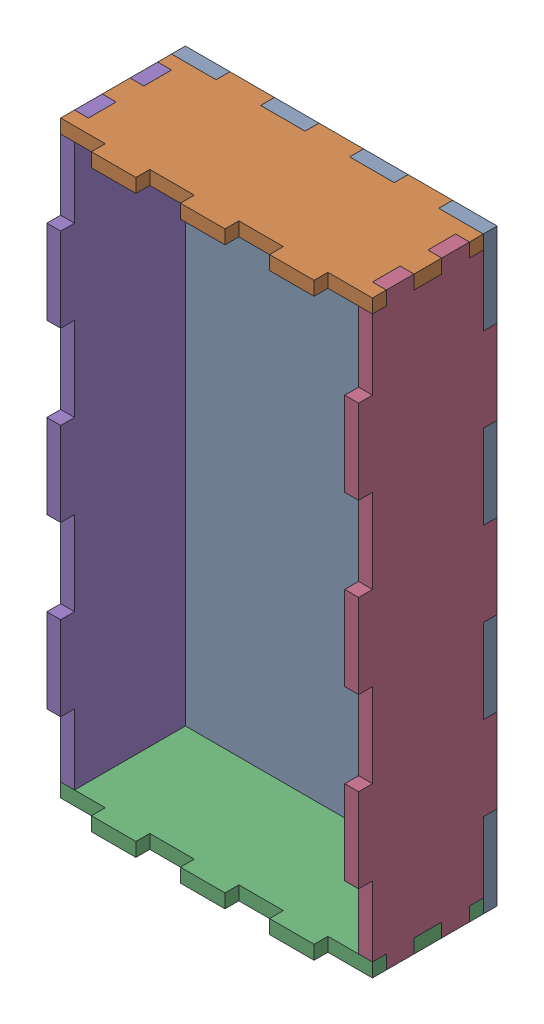
SolidWorks assembly Assem4, configuration Default. Lengths in mm.
Overall size (90 170 40).
5 component instances, 3 part files, 12 mates.
Components (placement in the parent):
- achterkant tetris-1: achterkant tetris [Default] at (-13.1878 -75.2557 -21.407) size (90 170 4)
- boven tetris-1: boven tetris [Default] at (-13.1878 94.7443 14.593) x (1 0 0) z (0 1 0) size (90 40 4)
- boven tetris-2: boven tetris [Default] at (-13.1878 -75.2557 -25.407) x (1 0 0) z (0 -1 0) size (90 40 4)
- zijkant tetris-1: zijkant tetris [Default] at (72.8122 -75.2557 -25.407) x (0 0 1) z (-1 0 0) size (40 170 4)
- zijkant tetris-2: zijkant tetris [Default] at (-13.1878 -75.2557 -25.407) x (0 0 1) z (-1 0 0) size (40 170 4)
Mates (geometry in assembly coordinates):
- Coincident1: coincident: plane of achterkant tetris-1 through (25.3836 90.7443 -25.407) normal (0 1 0); plane of boven tetris-1 through (-13.1878 90.7443 14.593) normal (0 -1 0)
- Coincident2: coincident: line of achterkant tetris-1 through (51.0979 94.7443 -21.407) axis (-1 0 0); line of boven tetris-1 through (38.2408 94.7443 -21.407) axis (1 0 0)
- Coincident3: coincident: point of achterkant tetris-1; point of boven tetris-1
- Coincident4: coincident: plane of achterkant tetris-1 through (25.3836 -71.2557 -25.407) normal (0 -1 0); plane of boven tetris-2 through (-13.1878 -71.2557 -25.407) normal (0 1 0)
- Coincident5: coincident: line of achterkant tetris-1 through (38.2408 -75.2557 -21.407) axis (1 0 0); line of boven tetris-2 through (51.0979 -75.2557 -21.407) axis (-1 0 0)
- Coincident6: coincident: point of achterkant tetris-1; point of boven tetris-2
- Coincident7: coincident: plane of boven tetris-1 through (72.8122 90.7443 -1.407) normal (1 0 0); plane of zijkant tetris-1 through (72.8122 -75.2557 -25.407) normal (-1 0 0)
- Coincident8: coincident: line of achterkant tetris-1 through (72.8122 70.4585 -25.407) axis (0 -1 0); line of zijkant tetris-1 through (72.8122 70.4585 -25.407) axis (0 -1 0)
- Coincident9: coincident: point of boven tetris-2; point of zijkant tetris-1
- Coincident10: coincident: plane of boven tetris-1 through (-9.1878 90.7443 -17.407) normal (-1 0 0); plane of zijkant tetris-2 through (-9.1878 -75.2557 -25.407) normal (1 0 0)
- Coincident11: coincident: line of boven tetris-2 through (-9.1878 -75.2557 -1.407) axis (0 0 1); line of zijkant tetris-2 through (-9.1878 -75.2557 -1.407) axis (0 0 1)
- Coincident12: coincident: point of achterkant tetris-1; point of zijkant tetris-2
